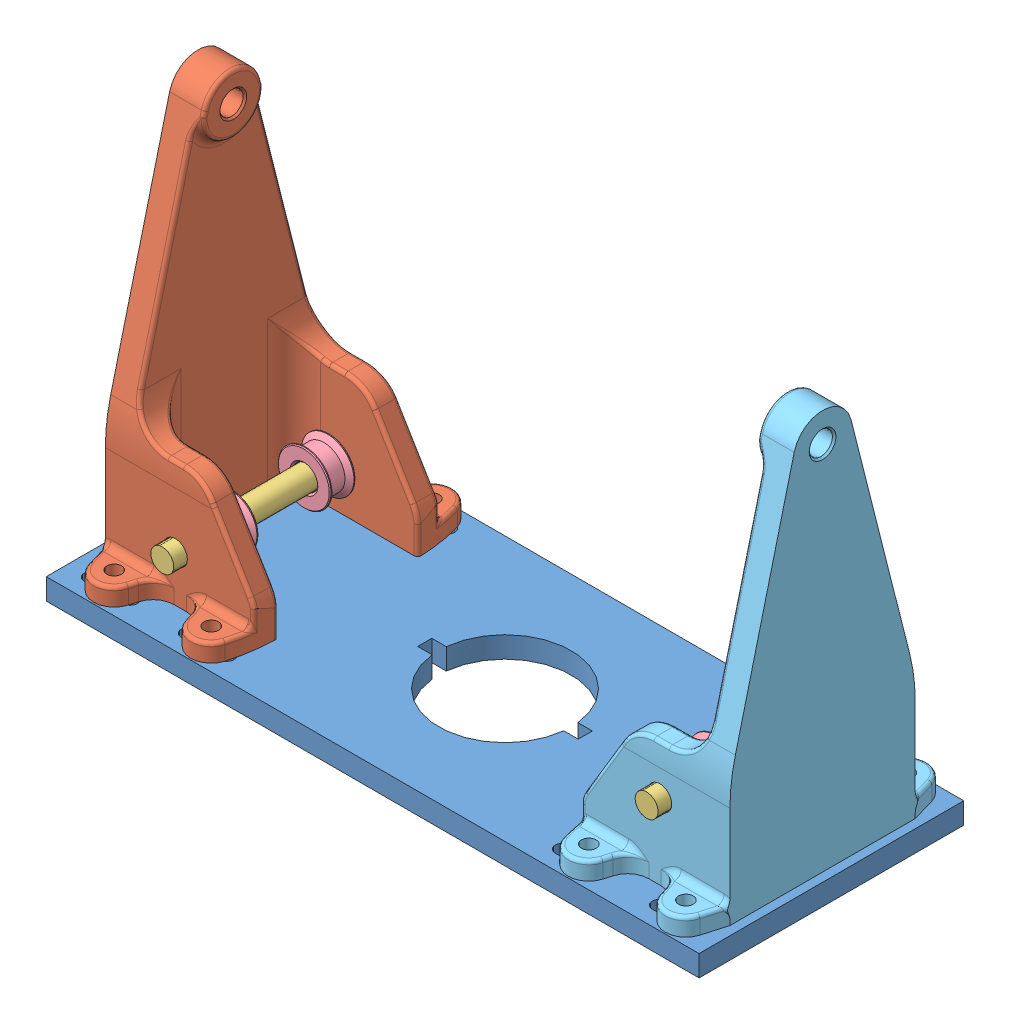
SolidWorks assembly outer plate assembly v5, configuration Default. Lengths in mm.
Overall size (370 238.6 150).
11 component instances, 5 part files, 7 mates.
Components (placement in the parent):
- outer plate base v5-1: outer plate base v5 [Default] at origin size (370 12 150)
- south outer plate pillar assembly v5-3: south outer plate pillar assembly v5 [Default] at (-174 47 0) x (0 0 -1) z (1 0 0) size (148.3 226.6 85.39)
  - south outer plate pillar v5-1: south outer plate pillar v5 [Default] at origin size (148.3 226.6 85.39)
  - outer plate rod v5-1: outer plate rod v5 [Default] at (0 -9 39.75) x (0 0.999711 0.024037) z (1 0 0) size (13 13 120)
  - outer plate idler v5-1: outer plate idler v5 [Default] at (27.5 -9 39.75) x (0 -0.999066 0.04321) z (1 0 0) size (29.8 29.8 14.5)
  - outer plate idler v5-2: outer plate idler v5 [Default] at (-27.5 -9 39.75) x (0 -0.85589 -0.517158) z (1 0 0) size (29.8 29.8 14.5)
- north outer plate pillar assembly v5-1: north outer plate pillar assembly v5 [Default] at (180 47 0) x (0 0 1) z (-1 0 0) size (148.3 226.6 85.39)
  - north outer plate pillar v5-1: north outer plate pillar v5 [Default] at origin size (148.3 226.6 85.39)
  - outer plate rod v5-1: outer plate rod v5 [Default] at (0 8 39.75) x (0 0.076905 -0.997038) z (1 0 0) size (13 13 120)
  - outer plate idler v5-1: outer plate idler v5 [Default] at (27.5 8 39.75) x (0 -0.999066 0.04321) z (1 0 0) size (29.8 29.8 14.5)
  - outer plate idler v5-2: outer plate idler v5 [Default] at (-27.5 8 39.75) x (0 -0.85589 -0.517158) z (1 0 0) size (29.8 29.8 14.5)
Mates (geometry in assembly coordinates):
- Coincident15: coincident anti-aligned: plane of outer plate base v5-1 through (0 12 0) normal (0 1 0); plane of south outer plate pillar assembly v5-3/south outer plate pillar v5-1 through (-159 12 0) normal (0 -1 0)
- Coincident16: coincident anti-aligned: plane of outer plate base v5-1 through (0 12 0) normal (0 1 0); plane of north outer plate pillar assembly v5-1/north outer plate pillar v5-1 through (165 12 0) normal (0 -1 0)
- Coincident17: coincident anti-aligned: plane of outer plate base v5-1 through (0 0 0) normal (0 0 1); plane of south outer plate pillar assembly v5-3 through (-174 47 0) normal (0 0 -1)
- Coincident18: coincident aligned: plane of outer plate base v5-1 through (0 0 0) normal (0 0 1); plane of north outer plate pillar assembly v5-1 through (180 47 0) normal (0 0 1)
- Distance2: distance = 5 mm aligned: plane of north outer plate pillar assembly v5-1/north outer plate pillar v5-1 through (180 47 0) normal (1 0 0); plane of outer plate base v5-1 through (185 12 -75) normal (1 0 0)
- Distance3: distance = 11 mm aligned: plane of outer plate base v5-1 through (-185 12 -75) normal (-1 0 0); plane of south outer plate pillar assembly v5-3/south outer plate pillar v5-1 through (-174 47 0) normal (-1 0 0)
- Coincident20: coordinate: point of outer plate base v5-1
